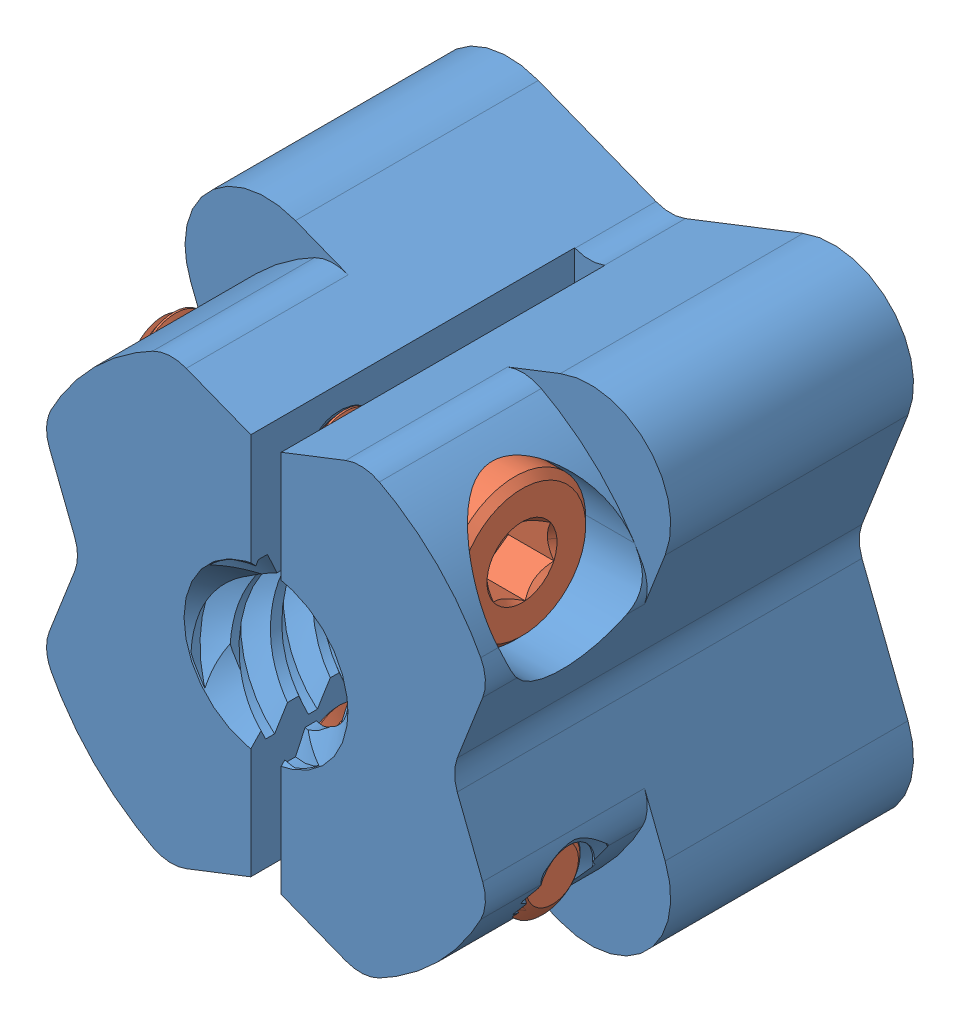
SolidWorks assembly Hyper Hub (4 Start, 8mm Lead Screw Bore)1310-0016-5008, configuration Default. Lengths in mm.
Overall size (24 24 22).
3 component instances, 2 part files, 0 mates.
Components (placement in the parent):
- 1310-0016-5008 REV1.STEP-1: 1310-0016-5008 REV1.STEP [Default] at (-35.111 8.5162 3.7593) size (24 24 22)
- 2800-0004-0014_90128A207.STEP-1: 2800-0004-0014_90128A207.STEP [Default] at (-25.361 2.2162 19.3593) x (0 0 -1) z (1 0 0) size (7 7 18.01)
- 2800-0004-0014_90128A207.STEP-2: 2800-0004-0014_90128A207.STEP [Default] at (-44.861 14.8162 19.3593) x (0 -0.092391 0.995723) z (-1 0 0) size (7 7 18.01)
